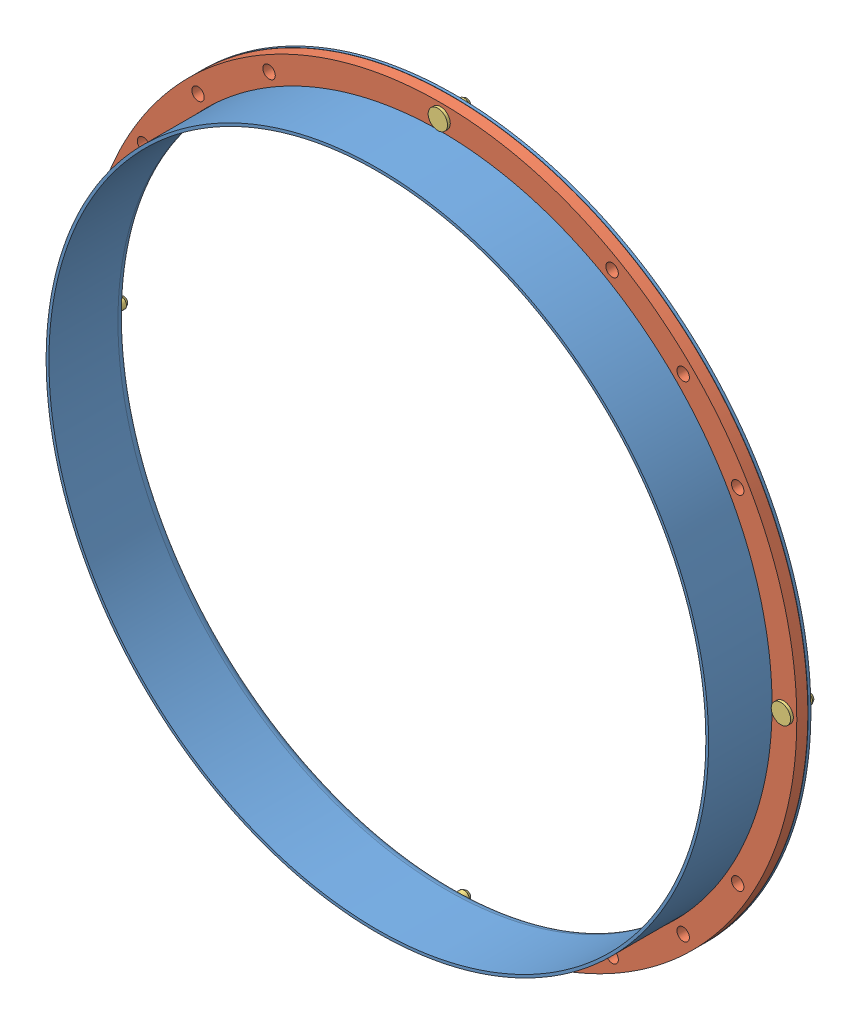
SolidWorks assembly MSC_Small_Flange_asm, configuration Default. Lengths in mm.
Overall size (258 258 32.4).
6 component instances, 3 part files, 9 mates.
Components (placement in the parent):
- MSC_Small_Flange_Base-1: MSC_Small_Flange_Base [Default] at origin size (258 258 28)
- MSC_Small_Flange_Backer-1: MSC_Small_Flange_Backer [Default] at (0 0 1.1) size (258 258 4.12)
- IDS Flange Alignment Pin-1: IDS Flange Alignment Pin [MSC short] at (0 124.25 5.1) x (0 0 -1) z (1 0 0) size (10.5 7 7)
- IDS Flange Alignment Pin-2: IDS Flange Alignment Pin [MSC short] at (-124.25 0 5.1) x (0 0 -1) z (0 1 0) size (10.5 7 7)
- IDS Flange Alignment Pin-3: IDS Flange Alignment Pin [MSC short] at (0 -124.25 5.1) x (0 0 -1) z (-1 0 0) size (10.5 7 7)
- IDS Flange Alignment Pin-4: IDS Flange Alignment Pin [MSC short] at (124.25 0 5.1) x (0 0 -1) z (0 -1 0) size (10.5 7 7)
Mates (geometry in assembly coordinates):
- Distance1: distance = 0.1 mm anti-aligned: plane of MSC_Small_Flange_Base-1 through (0 121.95 1) normal (0 0 1); plane of MSC_Small_Flange_Backer-1 through (0 129 1.1) normal (0 0 -1)
- Coincident1: coincident aligned: plane of MSC_Small_Flange_Base-1 through (0 0 0) normal (0 0 1); plane of assembly through (0 0 0) normal (0 0 1)
- Coincident2: coincident aligned: plane of MSC_Small_Flange_Base-1 through (0 0 0) normal (0 1 0); plane of assembly through (0 0 0) normal (0 1 0)
- Coincident3: coincident aligned: plane of MSC_Small_Flange_Base-1 through (0 0 0) normal (1 0 0); plane of assembly through (0 0 0) normal (1 0 0)
- Coincident4: coincident aligned: plane of MSC_Small_Flange_Backer-1 through (0 0 1.1) normal (0 1 0); plane of assembly through (0 0 0) normal (0 1 0)
- Coincident5: coincident aligned: plane of MSC_Small_Flange_Backer-1 through (0 0 1.1) normal (1 0 0); plane of assembly through (0 0 0) normal (1 0 0)
- Concentric1: concentric aligned: cylinder of MSC_Small_Flange_Backer-1 through (0 124.25 5.1) axis (0 0 1) radius 2; cylinder of IDS Flange Alignment Pin-1 through (0 124.25 35.2671) axis (0 0 1) radius 2.0025
- Coincident6: coincident anti-aligned: plane of MSC_Small_Flange_Backer-1 through (0 129 5.1) normal (0 0 1); plane of IDS Flange Alignment Pin-1 through (0 126.2525 5.1) normal (0 0 -1)
- Parallel1: parallel aligned: plane of IDS Flange Alignment Pin-1; plane of assembly through (0 0 0) normal (0 1 0)
